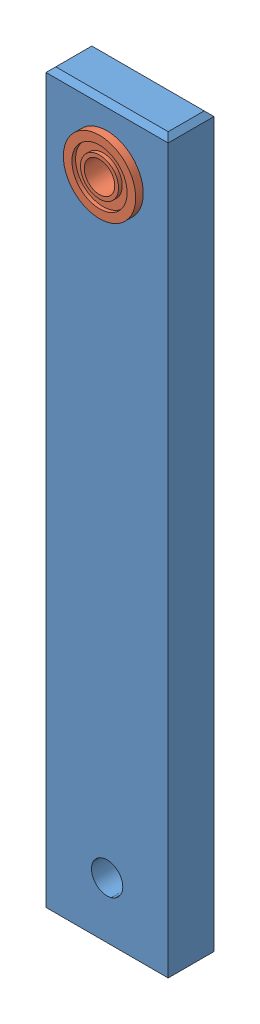
SolidWorks assembly top_link_assy, configuration Default. Lengths in mm.
Overall size (12.7 76.2 6.34).
3 component instances, 2 part files, 17 mates.
Components (placement in the parent):
- top_link-1: top_link [Default] at (0 -6.35 4.7625) x (0 1 0) z (-1 0 0) size (76.2 4.76 12.7)
- FR144-ZZ-3: FR144-ZZ [Default] at (0 -6.35 2.7464) x (-0.97513 -0.221634 0) z (0 0 1) size (7.52 7.52 2.8)
- FR144-ZZ-4: FR144-ZZ [Default] at (0 -6.35 2.0161) x (0.985651 0.168793 0) z (0 0 -1) size (7.52 7.52 2.8)
Mates (geometry in assembly coordinates):
- Parallel1: parallel: plane of top_link-1 through (-6.35 -6.35 0) normal (-1 0 0); plane of ? through (-2.3813 -4.9752 -0.9652) normal (-1 0 0)
- Coincident12: coincident anti-aligned: plane of top_link-1 through (0 0 4.7625) normal (0 0 1); plane of ? through (-0.075 -2.7041 4.7625) normal (0 0 -1)
- Concentric12: concentric anti-aligned: cylinder of top_link-1 through (0 0 0) axis (0 0 -1) radius 1.632; cylinder of ? through (0 0 6.2611) axis (0 0 1) radius 2.7051
- Concentric13: concentric anti-aligned: circle of ?; circle of ?
- Symmetric1: symmetric aligned: plane of top_link-1 through (-6.35 -6.35 0) normal (-1 0 0); plane of top_link-1 through (6.35 -6.35 0) normal (1 0 0); plane of assembly through (0 0 0) normal (1 0 0)
- Coincident34: coincident anti-aligned: plane of top_link-1 through (0 -6.35 0) normal (0 0 -1); plane of assembly through (0 0 0) normal (0 0 1)
- Concentric26: concentric aligned: cylinder of top_link-1 through (0 -6.35 4.7625) axis (0 0 1) radius 1.632; cylinder of ? through (0 -6.35 4.7625) axis (0 0 1) radius 3.2385
- Coincident38: coincident aligned: plane of top_link-1 through (0 -6.35 4.7625) normal (0 0 1); plane of ? through (0 -7.7724 4.7625) normal (0 0 1)
- Concentric27: concentric anti-aligned: cylinder of top_link-1 through (0 -6.35 4.7625) axis (0 0 1) radius 1.632; circle of ?
- Coincident39: coincident: plane of ? through (-2.3813 -4.9752 -0.9652) normal (0 0 1); plane of ? through (0 -6.35 -0.9652) normal (0 0 -1)
- Coincident40: coincident anti-aligned: plane of top_link-1 through (0 -6.35 0) normal (0 0 -1); plane of ? through (0 -6.35 0) normal (0 0 1)
- Coincident41: coincident aligned: plane of top_link-1 through (0 0 0) normal (0 1 0); plane of assembly through (0 0 0) normal (0 1 0)
- Concentric28: concentric anti-aligned: cylinder of top_link-1 through (0 -6.35 4.7625) axis (0 0 1) radius 1.632; cylinder of ? through (0 -6.35 0) axis (0 0 -1) radius 1.5875
- Coincident42: coincident anti-aligned: plane of top_link-1 through (0 -6.35 4.7625) normal (0 0 1); plane of FR144-ZZ-3 through (0 -6.35 4.7625) normal (0 0 -1)
- Concentric29: concentric aligned: cylinder of top_link-1 through (0 -6.35 4.7625) axis (0 0 -1) radius 3.1623; cylinder of FR144-ZZ-3 through (0 -6.35 4.7625) axis (0 0 -1) radius 3.175
- Coincident43: coincident anti-aligned: plane of top_link-1 through (0 -6.35 0) normal (0 0 -1); plane of FR144-ZZ-4 through (0 -6.35 0) normal (0 0 1)
- Concentric30: concentric anti-aligned: cylinder of top_link-1 through (0 -6.35 4.7625) axis (0 0 -1) radius 3.1623; cylinder of FR144-ZZ-4 through (0 -6.35 0) axis (0 0 1) radius 3.175
